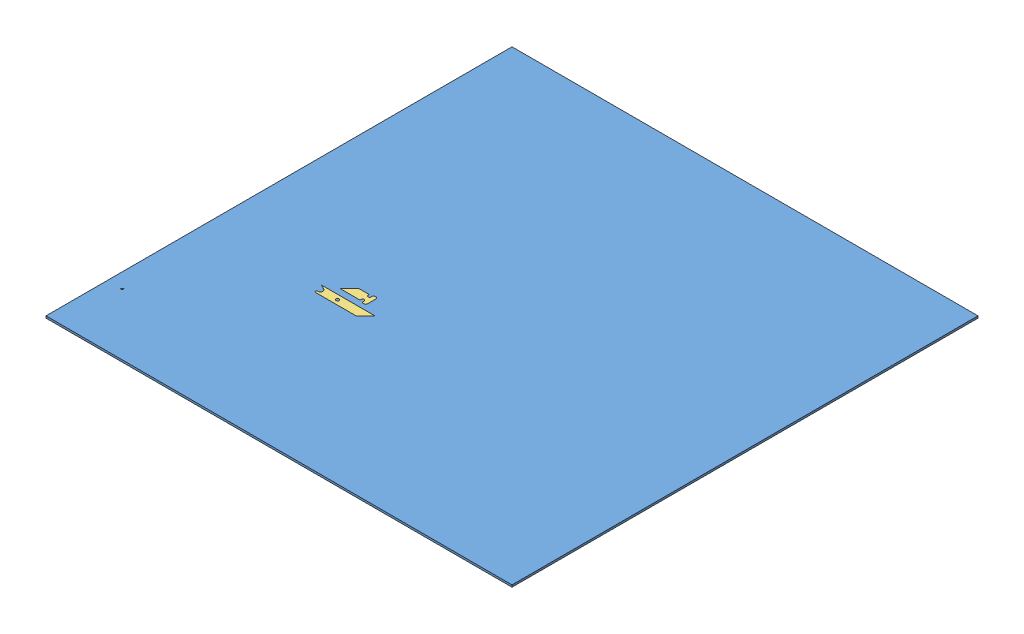
SolidWorks assembly 1.2mm-milling-assembly, configuration Default. Lengths in mm.
Overall size (298 1.3 298).
5 component instances, 3 part files, 16 mates.
Components (placement in the parent):
- stock-1.2mm-1: stock-1.2mm [Default] at origin size (298 1.3 298)
- frame-bottom-1: frame-bottom [Default] at (85.6802 1.3 84.6802) x (-1 0 0) z (0 -1 0) size (124.64 124.64 1.3)
- camera-protector-1: camera-protector [Default] at (-67.0934 0 147) x (0 0 -1) z (1 0 0) size (92.13 1.3 149.85)
- camera-protector-2: camera-protector [Default] at (71.9546 0 43.865) x (0 0 1) z (-1 0 0) size (92.13 1.3 149.85)
- camera-protector-3: camera-protector [Default] at (-145 0 -38.159) size (92.13 1.3 149.85)
Mates (geometry in assembly coordinates):
- Coincident1: coincident aligned: plane of stock-1.2mm-1 through (0 0 0) normal (0 -1 0); plane of frame-bottom-1 through (85.6802 0 84.6802) normal (0 -1 0)
- Parallel1: parallel anti-aligned: plane of frame-bottom-1; plane of assembly through (0 0 0) normal (1 0 0)
- Distance4: distance = 1 mm aligned: plane of stock-1.2mm-1 through (149 1.3 -149) normal (1 0 0); cylinder of frame-bottom-1 through (117.5 0 116.5) axis (0 1 0) radius 30.5
- Coincident3: coincident aligned: plane of stock-1.2mm-1 through (0 0 0) normal (0 -1 0); plane of ? through (-37.7149 0 54.0184) normal (0 -1 0)
- Parallel3: parallel aligned: plane of stock-1.2mm-1 through (-124.5 1.2 97.5) normal (0 0 1); plane of ? through (-56.9649 1.75 65.8934) normal (0 0 1)
- Tangent8: tangent aligned: cylinder of frame-bottom-1 through (117.5 0 116.5) axis (0 1 0) radius 30.5; plane of assembly through (0 0 147) normal (0 0 1)
- Tangent9: tangent aligned: cylinder of ? through (-4.094 1.75 88.85) axis (0 -1 0) radius 7.65; plane of assembly through (0 0 96.5) normal (0 0 1)
- Coincident4: coincident aligned: plane of stock-1.2mm-1 through (0 0 0) normal (0 -1 0); plane of camera-protector-1 through (7.9306 0 136.9517) normal (0 -1 0)
- Distance6: distance = 2 mm aligned: plane of camera-protector-1 through (13.3679 1.3196 147) normal (0 0 1); plane of stock-1.2mm-1 through (-149 1.3 149) normal (0 0 1)
- Distance7: distance = 5 mm: cylinder of camera-protector-1 through (80.4546 -0.001 141.5) axis (0 1 0) radius 1; cylinder of frame-bottom-1 through (53.8604 0 116.5) axis (0 1 0) radius 30.5
- Coincident7: coincident aligned: plane of stock-1.2mm-1 through (0 0 0) normal (0 -1 0); plane of camera-protector-2 through (-3.0694 0 53.9133) normal (0 -1 0)
- Distance8: distance = 5 mm anti-aligned: plane of camera-protector-2 through (-2.9694 0 136) normal (0 0 1); plane of camera-protector-1 through (2.4933 1.3196 141) normal (0 0 -1)
- Distance9: distance = 5 mm anti-aligned: plane of camera-protector-1 through (4.9306 0 223.63) normal (-1 0 0); plane of camera-protector-2 through (-0.0694 0 -32.765) normal (1 0 0)
- Coincident8: coincident aligned: plane of stock-1.2mm-1 through (0 0 0) normal (0 -1 0); plane of camera-protector-3 through (-134.9517 0 36.865) normal (0 -1 0)
- Distance10: distance = 4 mm aligned: plane of camera-protector-3 through (-145 1.3196 42.3023) normal (-1 0 0); plane of stock-1.2mm-1 through (-149 1.3 -149) normal (-1 0 0)
- Distance11: distance = 4 mm anti-aligned: plane of camera-protector-3 through (-136.1456 0 39.865) normal (0 0 1); plane of camera-protector-2 through (-8.5067 1.3196 43.865) normal (0 0 -1)
